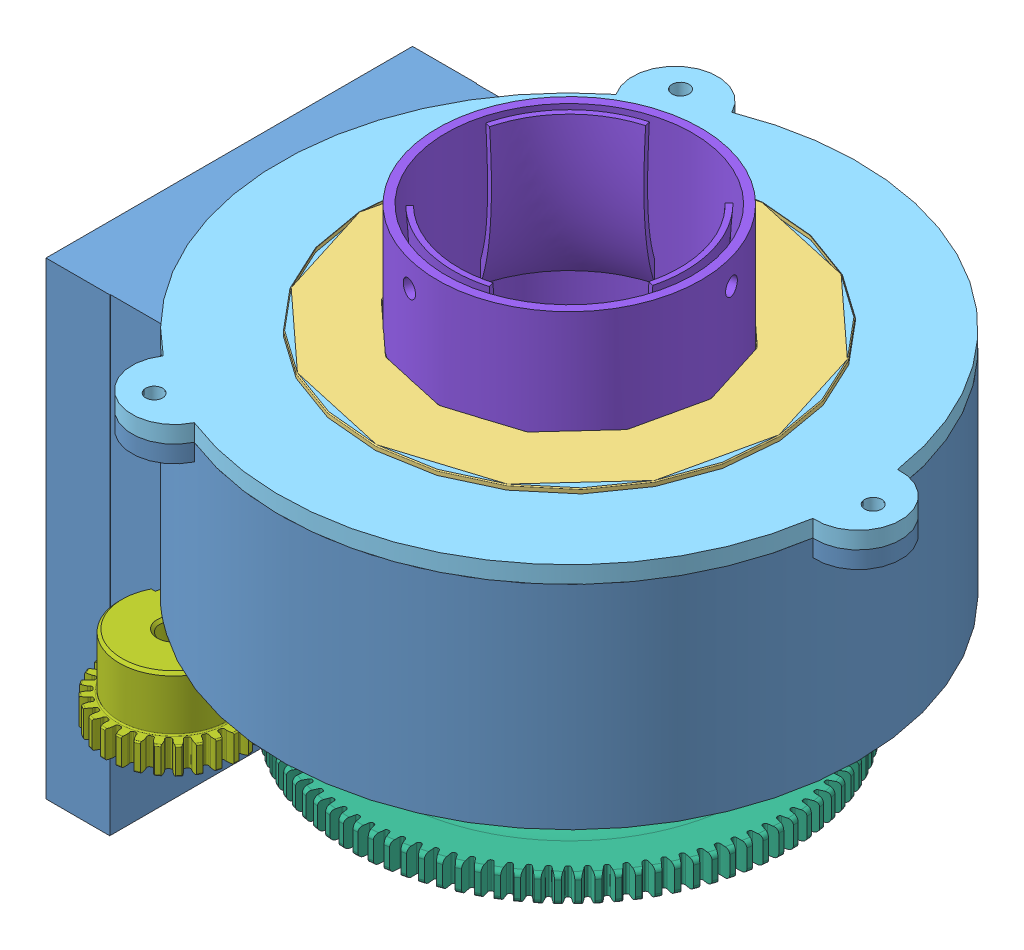
SolidWorks assembly Assem2ndversion, configuration Default. Lengths in mm.
Overall size (80.95 69.83 73.77).
8 component instances, 8 part files, 16 mates.
Components (placement in the parent):
- holder1-1: holder1 [Default] at (-40.135 12.2682 -5.2294) size (79 55.12 68.89)
- 5709K85_TAPERED-ROLLER BEARING WITH STEEL RING-1: 5709K85_TAPERED-ROLLER BEARING WITH STEEL RING [5709K85] at (-0.135 29.7337 -5.2294) x (-0.984693 0 -0.174295) z (0 -1 0) size (59.13 59.13 17.98)
- 6655K240_PLASTIC THRUST BALL BEARING-1: 6655K240_PLASTIC THRUST BALL BEARING [6655K24] at (-0.135 42.8231 -5.2294) x (-0.536254 0 -0.844056) z (0.844056 0 -0.536254) size (47.62 11.1 47.62)
- 6655K240_PLASTIC THRUST BALL BEARING - Copy-2: 6655K240_PLASTIC THRUST BALL BEARING - Copy [6655K24] at (-0.135 49.5281 -5.2294) x (0.507602 0 0.861592) z (-0.861592 0 0.507602) size (47.62 1.85 47.62)
- Part3-1: Part3 [Default] at (-0.135 47.8282 -5.2294) x (0.998123 0 0.06124) z (0 -1 0) size (72.94 69.43 8)
- 57655K310_PLASTIC GEAR--14-.5 DEG PRESSURE ANGLE-1: 57655K310_PLASTIC GEAR--14-.5 DEG PRESSURE ANGLE [57655K31] at (-0.135 10.5082 -5.2294) x (-0.969044 0 -0.246889) z (0 1 0) size (51.88 51.88 14.73)
- 57655K170_PLASTIC GEAR--14-.5 DEG PRESSURE ANGLE-1: 57655K170_PLASTIC GEAR--14-.5 DEG PRESSURE ANGLE [57655K17] at (-22.4427 8.7131 19.0351) x (1 0 0) z (0 -1 0) size (15.77 15.77 9.54)
- central holder_2 (1)-1: central holder_2 (1) [57655K31] at (-0.135 39.7032 -5.2294) x (0.51064 0 0.859795) z (0 -1 0) size (44.45 44.45 45.48)
Mates (geometry in assembly coordinates):
- Concentric1: concentric anti-aligned: cylinder of holder1-1 through (-0.135 20.8282 -5.2294) axis (0 1 0) radius 25; cylinder of 5709K85_TAPERED-ROLLER BEARING WITH STEEL RING-1 through (-0.135 29.7337 -5.2294) axis (0 -1 0) radius 29.5672
- Concentric3: concentric aligned: cylinder of 5709K85_TAPERED-ROLLER BEARING WITH STEEL RING-1 through (-0.135 29.7337 -5.2294) axis (0 -1 0) radius 15.875; cylinder of 6655K240_PLASTIC THRUST BALL BEARING-1 through (-0.135 37.2732 -5.2294) axis (0 -1 0) radius 15.9131
- Concentric4: concentric aligned: cylinder of 6655K240_PLASTIC THRUST BALL BEARING-1 through (-0.135 37.2732 -5.2294) axis (0 -1 0) radius 15.9131; cylinder of 6655K240_PLASTIC THRUST BALL BEARING - Copy-2 through (-0.135 43.9782 -5.2294) axis (0 -1 0) radius 15.9131
- Concentric5: concentric anti-aligned: cylinder of 5709K85_TAPERED-ROLLER BEARING WITH STEEL RING-1 through (-0.135 29.7337 -5.2294) axis (0 -1 0) radius 15.875; cylinder of Part3-1 through (-0.135 45.8282 -5.2294) axis (0 1 0) radius 34
- Coincident3: coincident anti-aligned: plane of 6655K240_PLASTIC THRUST BALL BEARING - Copy-2 through (-20.6517 45.8282 6.8579) normal (0 1 0); plane of Part3-1 through (-8.635 45.8282 9.4931) normal (0 -1 0)
- Concentric6: concentric aligned: cylinder of holder1-1 through (35.615 43.8282 -5.2294) axis (0 1 0) radius 1; cylinder of Part3-1 through (35.615 45.8282 -5.2294) axis (0 1 0) radius 1
- Concentric11: concentric anti-aligned: cylinder of the cap-1 through (129.7132 49.8632 -64.4611) axis (0 -1 0) radius 14.502; cone of Thecap-2 through (129.7132 50.5535 -64.4611) axis (0 1 0)
- Coincident4: coincident anti-aligned: plane of 5709K85_TAPERED-ROLLER BEARING WITH STEEL RING-1 through (2.6319 39.7032 -20.8614) normal (0 1 0); plane of the cap-1 through (129.7132 39.7032 -64.4611) normal (0 -1 0)
- Coincident5: coincident anti-aligned: plane of holder1-1 through (-0.135 23.8282 -5.2294) normal (0 1 0); plane of 5709K85_TAPERED-ROLLER BEARING WITH STEEL RING-1 through (5.0184 23.8282 -34.344) normal (0 -1 0)
- Parallel1: parallel anti-aligned: plane of holder1-1 through (-0.135 20.8282 -5.2294) normal (0 -1 0); plane of 57655K170_PLASTIC GEAR--14-.5 DEG PRESSURE ANGLE-1 through (-22.4427 18.2381 12.6851) normal (0 1 0)
- Concentric12: concentric aligned: cylinder of 5709K85_TAPERED-ROLLER BEARING WITH STEEL RING-1 through (-0.135 29.7337 -5.2294) axis (0 -1 0) radius 15.875; cylinder of central holder_2 (1)-1 through (-0.135 49.8632 -5.2294) axis (0 -1 0) radius 14.502
- Coincident6: coincident anti-aligned: plane of 5709K85_TAPERED-ROLLER BEARING WITH STEEL RING-1 through (2.6319 39.7032 -20.8614) normal (0 1 0); plane of central holder_2 (1)-1 through (-0.135 39.7032 -5.2294) normal (0 -1 0)
- Tangent1: tangent anti-aligned: sphere of 6655K240_PLASTIC THRUST BALL BEARING-1; plane of central holder_2 (1)-1 through (-0.135 40.9732 -5.2294) normal (0 1 0)
- Coincident7: coincident anti-aligned: plane of holder1-1 through (-0.135 45.8282 -5.2294) normal (0 1 0); plane of Part3-1 through (-8.635 45.8282 9.4931) normal (0 -1 0)
- Concentric13: concentric aligned: cylinder of 57655K310_PLASTIC GEAR--14-.5 DEG PRESSURE ANGLE-1 through (-0.135 19.0652 -5.2294) axis (0 -1 0) radius 15.75; cylinder of central holder_2 (1)-1 through (-0.135 49.8632 -5.2294) axis (0 -1 0) radius 14.502
- Concentric14: concentric anti-aligned: cylinder of 57655K310_PLASTIC GEAR--14-.5 DEG PRESSURE ANGLE-1 through (25.0016 17.0652 1.1748) axis (-0.969044 0 -0.246889) radius 1; cylinder of central holder_2 (1)-1 through (-18.5468 17.0652 -9.9203) axis (0.969044 0 0.246889) radius 1
